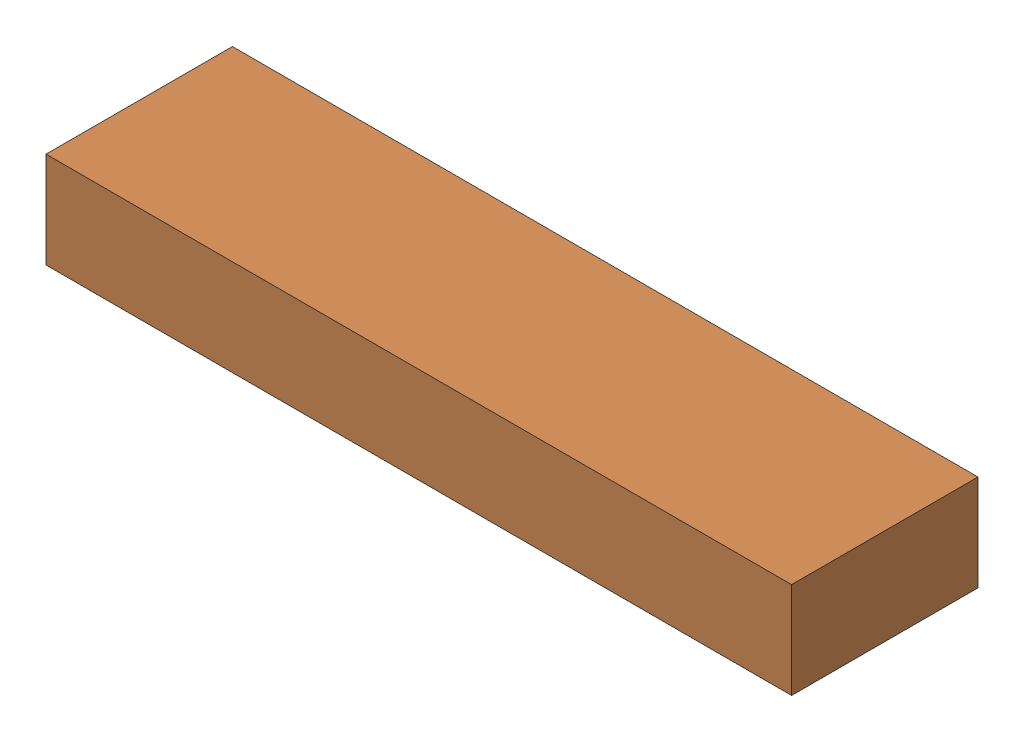
SolidWorks assembly SubmarinoCFD, configuration Default. Lengths in mm.
Overall size (16000 2060 4000).
2 component instances, 2 part files, 3 mates.
Components (placement in the parent):
- submarino-1: submarino [Default] at (-1826.5456 481.2179 636.9109) size (4356.11 508.08 730.27)
- Cubo-1: Cubo [Default] at (0 -440 750) size (16000 2060 4000)
Mates (geometry in assembly coordinates):
- Distance3: distance = 500 mm anti-aligned: plane of Cubo-1 through (0 -500 750) normal (0 -1 0)
- Distance1: distance = 8000 mm: plane of assembly through (0 0 0) normal (1 0 0); plane of assembly; plane of Cubo-1 through (8000 -500 2750) normal (1 0 0)
- Distance2: distance = 1250 mm: plane of assembly through (0 0 0) normal (0 0 1); plane of assembly; plane of Cubo-1 through (-8000 -500 -1250) normal (0 0 -1)
